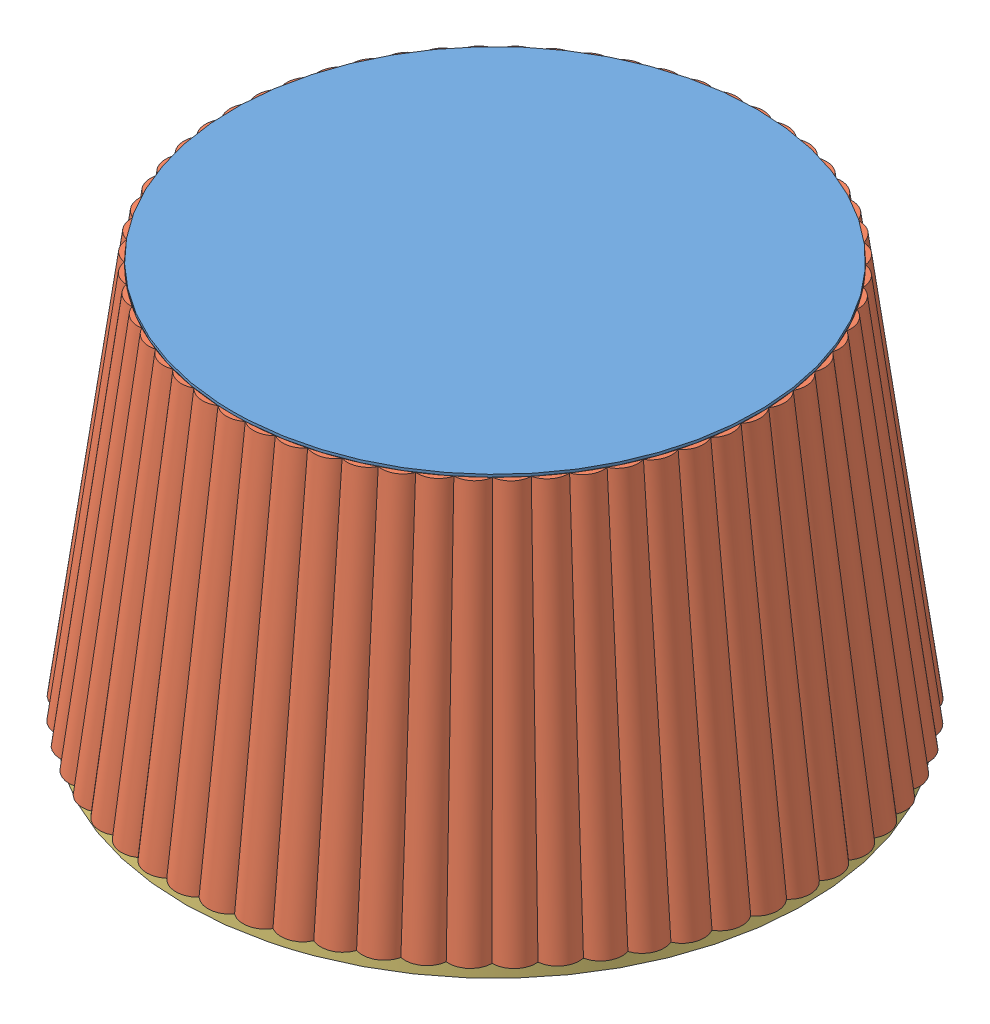
SolidWorks assembly bottom base assembled, configuration Default. Lengths in mm.
Overall size (76.65 39.62 76.65).
62 component instances, 3 part files, 5 mates.
Components (placement in the parent):
- very bottom-2: very bottom [Default] at (6.9568 41.998 35.8089) size (51.63 0.25 51.63)
- cupcake bottom mk2-2: cupcake bottom mk2 [Default] at (6.9568 3.898 35.8089) x (0.967604 0 -0.252473) z (0.252473 0 0.967604) size (3.21 38.11 5.58)
- cupcake bottom mk2-3: cupcake bottom mk2 [Default] at (6.9568 3.898 35.8089) x (0.935913 0 -0.352232) z (0.352232 0 0.935913) size (3.21 38.11 5.58)
- cupcake bottom mk2-4: cupcake bottom mk2 [Default] at (6.9568 3.898 35.8089) x (0.893967 0 -0.448132) z (0.448132 0 0.893967) size (3.21 38.11 5.58)
- cupcake bottom mk2-5: cupcake bottom mk2 [Default] at (6.9568 3.898 35.8089) x (0.842228 0 -0.539122) z (0.539122 0 0.842228) size (3.21 38.11 5.58)
- cupcake bottom mk2-6: cupcake bottom mk2 [Default] at (6.9568 3.898 35.8089) x (0.78126 0 -0.624205) z (0.624205 0 0.78126) size (3.21 38.11 5.58)
- cupcake bottom mk2-7: cupcake bottom mk2 [Default] at (6.9568 3.898 35.8089) x (0.711733 0 -0.70245) z (0.70245 0 0.711733) size (3.21 38.11 5.58)
- cupcake bottom mk2-8: cupcake bottom mk2 [Default] at (6.9568 3.898 35.8089) x (0.634408 0 -0.772998) z (0.772998 0 0.634408) size (3.21 38.11 5.58)
- cupcake bottom mk2-9: cupcake bottom mk2 [Default] at (6.9568 3.898 35.8089) x (0.550133 0 -0.835077) z (0.835077 0 0.550133) size (3.21 38.11 5.58)
- cupcake bottom mk2-10: cupcake bottom mk2 [Default] at (6.9568 3.898 35.8089) x (0.45983 0 -0.888007) z (0.888007 0 0.45983) size (3.21 38.11 5.58)
- cupcake bottom mk2-11: cupcake bottom mk2 [Default] at (6.9568 3.898 35.8089) x (0.364489 0 -0.931208) z (0.931208 0 0.364489) size (3.21 38.11 5.58)
- cupcake bottom mk2-12: cupcake bottom mk2 [Default] at (6.9568 3.898 35.8089) x (0.265154 0 -0.964206) z (0.964206 0 0.265154) size (3.21 38.11 5.58)
- cupcake bottom mk2-13: cupcake bottom mk2 [Default] at (6.9568 3.898 35.8089) x (0.162915 0 -0.98664) z (0.98664 0 0.162915) size (3.21 38.11 5.58)
- cupcake bottom mk2-14: cupcake bottom mk2 [Default] at (6.9568 3.898 35.8089) x (0.05889 0 -0.998264) z (0.998264 0 0.05889) size (3.21 38.11 5.58)
- cupcake bottom mk2-15: cupcake bottom mk2 [Default] at (6.9568 3.898 35.8089) x (-0.045779 0 -0.998952) z (0.998952 0 -0.045779) size (3.21 38.11 5.58)
- cupcake bottom mk2-16: cupcake bottom mk2 [Default] at (6.9568 3.898 35.8089) x (-0.149948 0 -0.988694) z (0.988694 0 -0.149948) size (3.21 38.11 5.58)
- cupcake bottom mk2-17: cupcake bottom mk2 [Default] at (6.9568 3.898 35.8089) x (-0.252473 0 -0.967604) z (0.967604 0 -0.252473) size (3.21 38.11 5.58)
- cupcake bottom mk2-18: cupcake bottom mk2 [Default] at (6.9568 3.898 35.8089) x (-0.352232 0 -0.935913) z (0.935913 0 -0.352232) size (3.21 38.11 5.58)
- cupcake bottom mk2-19: cupcake bottom mk2 [Default] at (6.9568 3.898 35.8089) x (-0.448132 0 -0.893967) z (0.893967 0 -0.448132) size (3.21 38.11 5.58)
- cupcake bottom mk2-20: cupcake bottom mk2 [Default] at (6.9568 3.898 35.8089) x (-0.539122 0 -0.842228) z (0.842228 0 -0.539122) size (3.21 38.11 5.58)
- cupcake bottom mk2-21: cupcake bottom mk2 [Default] at (6.9568 3.898 35.8089) x (-0.624205 0 -0.78126) z (0.78126 0 -0.624205) size (3.21 38.11 5.58)
- cupcake bottom mk2-22: cupcake bottom mk2 [Default] at (6.9568 3.898 35.8089) x (-0.70245 0 -0.711733) z (0.711733 0 -0.70245) size (3.21 38.11 5.58)
- cupcake bottom mk2-23: cupcake bottom mk2 [Default] at (6.9568 3.898 35.8089) x (-0.772998 0 -0.634408) z (0.634408 0 -0.772998) size (3.21 38.11 5.58)
- cupcake bottom mk2-24: cupcake bottom mk2 [Default] at (6.9568 3.898 35.8089) x (-0.835077 0 -0.550133) z (0.550133 0 -0.835077) size (3.21 38.11 5.58)
- cupcake bottom mk2-25: cupcake bottom mk2 [Default] at (6.9568 3.898 35.8089) x (-0.888007 0 -0.45983) z (0.45983 0 -0.888007) size (3.21 38.11 5.58)
- cupcake bottom mk2-26: cupcake bottom mk2 [Default] at (6.9568 3.898 35.8089) x (-0.931208 0 -0.364489) z (0.364489 0 -0.931208) size (3.21 38.11 5.58)
- cupcake bottom mk2-27: cupcake bottom mk2 [Default] at (6.9568 3.898 35.8089) x (-0.964206 0 -0.265154) z (0.265154 0 -0.964206) size (3.21 38.11 5.58)
- cupcake bottom mk2-28: cupcake bottom mk2 [Default] at (6.9568 3.898 35.8089) x (-0.98664 0 -0.162915) z (0.162915 0 -0.98664) size (3.21 38.11 5.58)
- cupcake bottom mk2-29: cupcake bottom mk2 [Default] at (6.9568 3.898 35.8089) x (-0.998264 0 -0.05889) z (0.05889 0 -0.998264) size (3.21 38.11 5.58)
- cupcake bottom mk2-30: cupcake bottom mk2 [Default] at (6.9568 3.898 35.8089) x (-0.998952 0 0.045779) z (-0.045779 0 -0.998952) size (3.21 38.11 5.58)
- cupcake bottom mk2-31: cupcake bottom mk2 [Default] at (6.9568 3.898 35.8089) x (-0.988694 0 0.149948) z (-0.149948 0 -0.988694) size (3.21 38.11 5.58)
- cupcake bottom mk2-32: cupcake bottom mk2 [Default] at (6.9568 3.898 35.8089) x (-0.967604 0 0.252473) z (-0.252473 0 -0.967604) size (3.21 38.11 5.58)
- cupcake bottom mk2-33: cupcake bottom mk2 [Default] at (6.9568 3.898 35.8089) x (-0.935913 0 0.352232) z (-0.352232 0 -0.935913) size (3.21 38.11 5.58)
- cupcake bottom mk2-34: cupcake bottom mk2 [Default] at (6.9568 3.898 35.8089) x (-0.893967 0 0.448132) z (-0.448132 0 -0.893967) size (3.21 38.11 5.58)
- cupcake bottom mk2-35: cupcake bottom mk2 [Default] at (6.9568 3.898 35.8089) x (-0.842228 0 0.539122) z (-0.539122 0 -0.842228) size (3.21 38.11 5.58)
- cupcake bottom mk2-36: cupcake bottom mk2 [Default] at (6.9568 3.898 35.8089) x (-0.78126 0 0.624205) z (-0.624205 0 -0.78126) size (3.21 38.11 5.58)
- cupcake bottom mk2-37: cupcake bottom mk2 [Default] at (6.9568 3.898 35.8089) x (-0.711733 0 0.70245) z (-0.70245 0 -0.711733) size (3.21 38.11 5.58)
- cupcake bottom mk2-38: cupcake bottom mk2 [Default] at (6.9568 3.898 35.8089) x (-0.634408 0 0.772998) z (-0.772998 0 -0.634408) size (3.21 38.11 5.58)
- cupcake bottom mk2-39: cupcake bottom mk2 [Default] at (6.9568 3.898 35.8089) x (-0.550133 0 0.835077) z (-0.835077 0 -0.550133) size (3.21 38.11 5.58)
- cupcake bottom mk2-40: cupcake bottom mk2 [Default] at (6.9568 3.898 35.8089) x (-0.45983 0 0.888007) z (-0.888007 0 -0.45983) size (3.21 38.11 5.58)
- cupcake bottom mk2-41: cupcake bottom mk2 [Default] at (6.9568 3.898 35.8089) x (-0.364489 0 0.931208) z (-0.931208 0 -0.364489) size (3.21 38.11 5.58)
- cupcake bottom mk2-42: cupcake bottom mk2 [Default] at (6.9568 3.898 35.8089) x (-0.265154 0 0.964206) z (-0.964206 0 -0.265154) size (3.21 38.11 5.58)
- cupcake bottom mk2-43: cupcake bottom mk2 [Default] at (6.9568 3.898 35.8089) x (-0.162915 0 0.98664) z (-0.98664 0 -0.162915) size (3.21 38.11 5.58)
- cupcake bottom mk2-44: cupcake bottom mk2 [Default] at (6.9568 3.898 35.8089) x (-0.05889 0 0.998264) z (-0.998264 0 -0.05889) size (3.21 38.11 5.58)
- cupcake bottom mk2-45: cupcake bottom mk2 [Default] at (6.9568 3.898 35.8089) x (0.045779 0 0.998952) z (-0.998952 0 0.045779) size (3.21 38.11 5.58)
- cupcake bottom mk2-46: cupcake bottom mk2 [Default] at (6.9568 3.898 35.8089) x (0.149948 0 0.988694) z (-0.988694 0 0.149948) size (3.21 38.11 5.58)
- cupcake bottom mk2-47: cupcake bottom mk2 [Default] at (6.9568 3.898 35.8089) x (0.252473 0 0.967604) z (-0.967604 0 0.252473) size (3.21 38.11 5.58)
- cupcake bottom mk2-48: cupcake bottom mk2 [Default] at (6.9568 3.898 35.8089) x (0.352232 0 0.935913) z (-0.935913 0 0.352232) size (3.21 38.11 5.58)
- cupcake bottom mk2-49: cupcake bottom mk2 [Default] at (6.9568 3.898 35.8089) x (0.448132 0 0.893967) z (-0.893967 0 0.448132) size (3.21 38.11 5.58)
- cupcake bottom mk2-50: cupcake bottom mk2 [Default] at (6.9568 3.898 35.8089) x (0.539122 0 0.842228) z (-0.842228 0 0.539122) size (3.21 38.11 5.58)
- cupcake bottom mk2-51: cupcake bottom mk2 [Default] at (6.9568 3.898 35.8089) x (0.624205 0 0.78126) z (-0.78126 0 0.624205) size (3.21 38.11 5.58)
- cupcake bottom mk2-52: cupcake bottom mk2 [Default] at (6.9568 3.898 35.8089) x (0.70245 0 0.711733) z (-0.711733 0 0.70245) size (3.21 38.11 5.58)
- cupcake bottom mk2-53: cupcake bottom mk2 [Default] at (6.9568 3.898 35.8089) x (0.772998 0 0.634408) z (-0.634408 0 0.772998) size (3.21 38.11 5.58)
- cupcake bottom mk2-54: cupcake bottom mk2 [Default] at (6.9568 3.898 35.8089) x (0.835077 0 0.550133) z (-0.550133 0 0.835077) size (3.21 38.11 5.58)
- cupcake bottom mk2-55: cupcake bottom mk2 [Default] at (6.9568 3.898 35.8089) x (0.888007 0 0.45983) z (-0.45983 0 0.888007) size (3.21 38.11 5.58)
- cupcake bottom mk2-56: cupcake bottom mk2 [Default] at (6.9568 3.898 35.8089) x (0.931208 0 0.364489) z (-0.364489 0 0.931208) size (3.21 38.11 5.58)
- cupcake bottom mk2-57: cupcake bottom mk2 [Default] at (6.9568 3.898 35.8089) x (0.964206 0 0.265154) z (-0.265154 0 0.964206) size (3.21 38.11 5.58)
- cupcake bottom mk2-58: cupcake bottom mk2 [Default] at (6.9568 3.898 35.8089) x (0.98664 0 0.162915) z (-0.162915 0 0.98664) size (3.21 38.11 5.58)
- cupcake bottom mk2-59: cupcake bottom mk2 [Default] at (6.9568 3.898 35.8089) x (0.998264 0 0.05889) z (-0.05889 0 0.998264) size (3.21 38.11 5.58)
- cupcake bottom mk2-60: cupcake bottom mk2 [Default] at (6.9568 3.898 35.8089) x (0.998952 0 -0.045779) z (0.045779 0 0.998952) size (3.21 38.11 5.58)
- cupcake bottom mk2-61: cupcake bottom mk2 [Default] at (6.9568 3.898 35.8089) x (0.988694 0 -0.149948) z (0.149948 0 0.988694) size (3.21 38.11 5.58)
- top of bottom-1: top of bottom [Default] at (6.9568 2.628 35.8089) x (0.954518 0 -0.298152) z (0.298152 0 0.954518) size (61.19 1.27 61.19)
Mates (geometry in assembly coordinates):
- Coincident2: coincident: circle of very bottom-2; plane of cupcake bottom mk2-2 through (4.5213 41.998 23.9677) normal (0 1 0)
- Coincident3: coincident: circle of very bottom-2; point of cupcake bottom mk2-2
- Coincident4: coincident: circle of very bottom-2; point of cupcake bottom mk2-2
- Coincident6: coincident: plane of cupcake bottom mk2-29 through (5.3416 3.898 50.2599) normal (0 -1 0); plane of top of bottom-1 through (6.9568 3.898 35.8089) normal (0 1 0)
- Concentric1: concentric: circle of very bottom-2; circle of top of bottom-1
